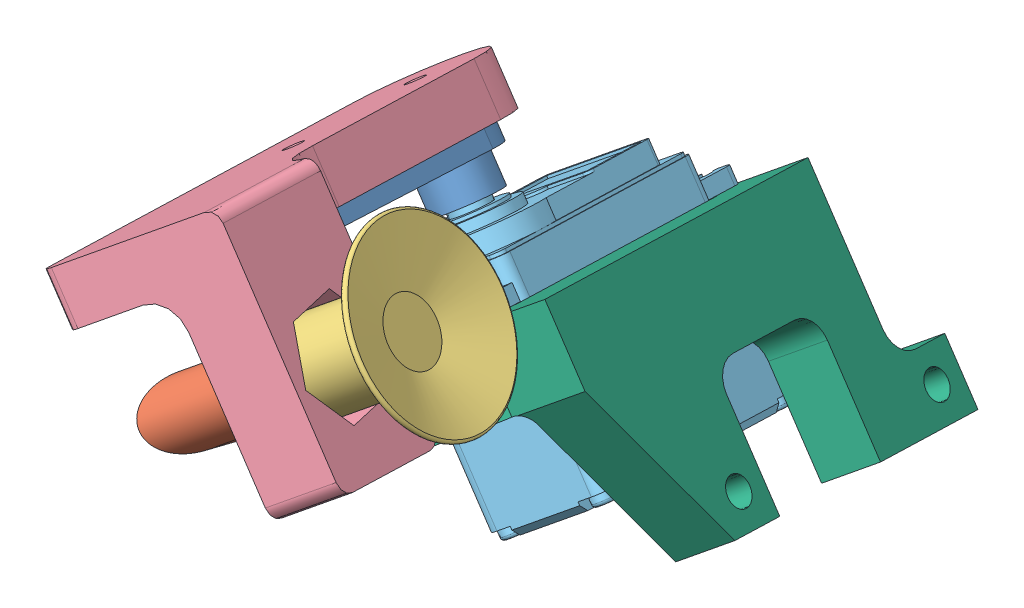
SolidWorks assembly 129_2, configuration Default. Lengths in mm.
Overall size (69.12 93.81 119.99).
6 component instances, 6 part files, 12 mates.
Components (placement in the parent):
- 2__v-2: 2__v [Default] at (14.891 32.4112 82.3442) x (-0.147581 -0.174863 -0.97347) z (-0.612276 0.789129 -0.048927) size (41 14 8)
- 128-1: 128 [Default] at (22.5053 29.3048 122.99) x (-0.06032 -0.283726 -0.957006) z (0.776748 0.588811 -0.223525) size (20 10 20)
- phan-1: phan [Défaut] at (51.3731 54.7579 129.2982) x (0.064793 -0.427731 -0.901581) z (0.626469 -0.685819 0.37039) size (29.46 25.39 29.46)
- 127_2-1: 127_2 [Default] at (15.896 45.7187 120.8915) x (-0.147581 -0.174863 -0.97347) z (-0.612276 0.789129 -0.048927) size (75 30.6 38)
- Servo-D-3: Servo-D [По умолчанию] at (37.297 -0.1111 74.5168) x (-0.147273 -0.17463 -0.973558) z (0.776807 0.58888 -0.223139) size (53 41.52 20)
- 159-1: 159 [Default] at (44.7205 22.1224 69.4057) x (0.147273 0.17463 0.973558) z (-0.776807 -0.58888 0.223139) size (64.9 36.5 29.5)
Mates (geometry in assembly coordinates):
- Coincident12: coincident anti-aligned: plane of 2__v-2 through (14.4202 43.9701 111.1568) normal (-0.612276 0.789129 -0.048927); plane of 127_2-1 through (9.9928 38.7242 81.9527) normal (0.612276 -0.789129 0.048927)
- Concentric8: concentric aligned: cylinder of 2__v-2 through (11.8296 36.3568 82.0995) axis (0.612276 -0.789129 0.048927) radius 3; cylinder of Servo-D-3 through (13.3603 34.384 82.2219) axis (0.612276 -0.789129 0.048927) radius 3
- Distance1: distance = 1 mm anti-aligned: plane of Servo-D-3 through (15.5033 31.6221 82.3931) normal (-0.612276 0.789129 -0.048927); plane of 2__v-2 through (14.891 32.4112 82.3442) normal (0.612276 -0.789129 0.048927)
- Concentric9: concentric aligned: cylinder of 128-1 through (19.0603 30.2634 138.5968) axis (0.776748 0.588811 -0.223525) radius 5; cylinder of phan-1 through (35.0613 42.3929 133.9922) axis (0.776748 0.588811 -0.223525) radius 6.75
- Coincident36: coincident anti-aligned: plane of Servo-D-3 through (27.817 34.5677 88.2193) normal (0.776807 0.58888 -0.223139); plane of 159-1 through (36.9524 16.2336 71.6371) normal (-0.776807 -0.58888 0.223139)
- Width6: width anti-aligned: plane of 159-1 through (24.8634 21.9746 44.7027) normal (-0.147273 -0.17463 -0.973558); plane of Servo-D-3 through (32.8161 31.4046 97.2749) normal (0.147273 0.17463 0.973558); plane of 159-1 through (26.558 33.7392 90.6127) normal (0.147273 0.17463 0.973558); plane of Servo-D-3 through (20.6671 26.754 51.6703) normal (-0.147273 -0.17463 -0.973558)
- Coincident37: coincident anti-aligned: plane of Servo-D-3 through (18.7352 20.5846 98.9714) normal (0.612276 -0.789129 0.048927); plane of 159-1 through (24.8634 21.9746 44.7027) normal (-0.612276 0.789129 -0.048927)
- Concentric10: concentric aligned: cylinder of 2__v-2 through (9.9928 38.7242 81.9527) axis (0.612276 -0.789129 0.048927) radius 7; cylinder of 127_2-1 through (5.0946 45.0373 81.5613) axis (0.612276 -0.789129 0.048927) radius 10
- Width7: width anti-aligned: plane of 127_2-1 through (6.9198 50.5152 147.0721) normal (-0.776748 -0.588811 0.223525); plane of 2__v-2 through (22.4548 62.2915 142.6016) normal (0.776748 0.588811 -0.223525); plane of 127_2-1 through (11.3132 41.6149 112.0509) normal (-0.758209 -0.56849 0.319279); plane of 2__v-2 through (17.5272 46.3254 110.2627) normal (0.787578 0.603289 -0.125551)
- Coincident39: coincident anti-aligned: plane of 128-1 through (35.0613 42.3929 133.9922) normal (0.776748 0.588811 -0.223525); plane of phan-1 through (35.0613 42.3929 133.9922) normal (-0.776748 -0.588811 0.223525)
- Coincident40: coincident anti-aligned: plane of phan-1 through (35.0613 42.3929 133.9922) normal (-0.776748 -0.588811 0.223525); plane of 127_2-1 through (23.6635 51.6069 118.6563) normal (0.776748 0.588811 -0.223525)
- Concentric11: concentric aligned: cylinder of phan-1 through (35.0613 42.3929 133.9922) axis (0.776748 0.588811 -0.223525) radius 6.75; cylinder of 127_2-1 through (27.2939 36.5048 136.2275) axis (0.776748 0.588811 -0.223525) radius 5.5
